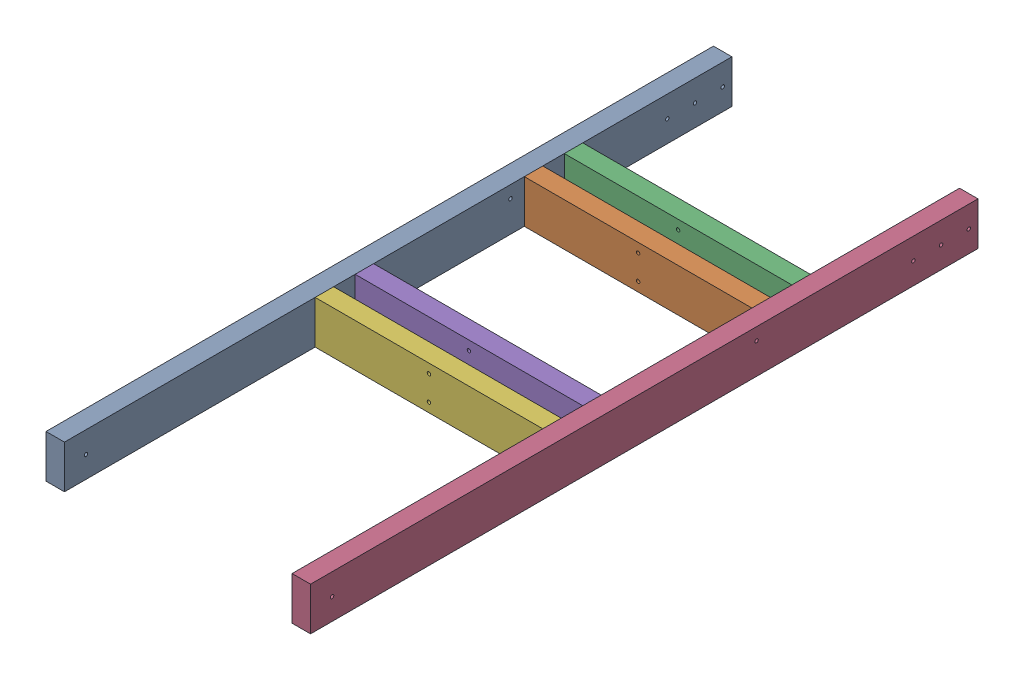
SolidWorks assembly TE-23031, configuration Default. Lengths in mm.
Overall size (546.1 88.9 1377.95).
6 component instances, 2 part files, 14 mates.
Components (placement in the parent):
- TE-23008-1: TE-23008 [Default] at (-254 44.45 0.7468) size (38.1 88.9 1377.95)
- TE-23010-2: TE-23010 [Default] at (-234.95 44.45 410.3218) x (0 0 -1) z (1 0 0) size (38.1 88.9 469.9)
- TE-23010-3: TE-23010 [Default] at (-234.95 44.45 327.7718) x (0 0 -1) z (1 0 0) size (38.1 88.9 469.9)
- TE-23008-2: TE-23008 [Default] at (254 44.45 0.7468) size (38.1 88.9 1377.95)
- TE-23010-4: TE-23010 [Default] at (-234.95 44.45 759.5718) x (0 0 -1) z (1 0 0) size (38.1 88.9 469.9)
- TE-23010-5: TE-23010 [Default] at (-234.95 44.45 842.1218) x (0 0 -1) z (1 0 0) size (38.1 88.9 469.9)
Mates (geometry in assembly coordinates):
- Coincident21: coincident aligned: plane of TE-23026-3 through (234.95 0 346.8218) normal (0 -1 0); plane of TE-23026-2 through (234.95 0 429.3718) normal (0 -1 0)
- Coincident25: coincident anti-aligned: plane of Cone Ramp Horizontal-1 through (-234.95 0 1378.6968) normal (1 0 0); plane of TE-23026-3 through (-234.95 44.45 327.7718) normal (-1 0 0)
- Coincident26: coincident anti-aligned: plane of Cone Ramp Horizontal-1 through (-234.95 0 1378.6968) normal (1 0 0); plane of TE-23026-2 through (-234.95 44.45 410.3218) normal (-1 0 0)
- Coincident34: coincident aligned: plane of Cone Ramp Horizontal-1 through (-273.05 0 1378.6968) normal (0 -1 0); plane of Cone Ramp Horizontal-2 through (234.95 0 1378.6968) normal (0 -1 0)
- Coincident36: coincident aligned: plane of Cone Ramp Horizontal-1 through (-254 44.45 0.7468) normal (0 0 -1); plane of Cone Ramp Horizontal-2 through (254 44.45 0.7468) normal (0 0 -1)
- Distance3: distance = 44.45 mm anti-aligned: plane of GE-23626-3 through (234.95 0 346.8218) normal (0 0 1); plane of GE-23626-2 through (234.95 0 391.2718) normal (0 0 -1)
- Distance5: distance = 307.975 mm aligned: plane of GE-23626-3 through (234.95 0 308.7218) normal (0 0 -1); plane of Cone Ramp Horizontal-1 through (-254 44.45 0.7468) normal (0 0 -1)
- Coincident41: coincident aligned: plane of TE-23011-1 through (-273.05 88.9 1378.6968) normal (0 1 0); plane of TE-23026-3 through (234.95 88.9 346.8218) normal (0 1 0)
- Coincident42: coincident aligned: plane of TE-23011-2 through (234.95 88.9 1378.6968) normal (0 1 0); plane of TE-23026-4 through (234.95 88.9 778.6218) normal (0 1 0)
- Distance6: distance = 311.15 mm anti-aligned: plane of TE-23026-4 through (234.95 0 740.5218) normal (0 0 -1); plane of TE-23026-2 through (234.95 0 429.3718) normal (0 0 1)
- Coincident44: coincident aligned: plane of TE-23011-1 through (-273.05 88.9 1378.6968) normal (0 1 0); plane of TE-23026-4 through (234.95 88.9 778.6218) normal (0 1 0)
- Distance7: distance = 44.45 mm anti-aligned: plane of TE-23026-4 through (234.95 0 778.6218) normal (0 0 1); plane of TE-23026-5 through (234.95 0 823.0718) normal (0 0 -1)
- Coincident46: coincident aligned: plane of TE-23026-4 through (234.95 88.9 778.6218) normal (0 1 0); plane of TE-23026-5 through (234.95 88.9 816.7218) normal (0 1 0)
- Coincident47: coincident anti-aligned: plane of TE-23011-1 through (-234.95 0 1378.6968) normal (1 0 0); plane of TE-23026-5 through (-234.95 44.45 797.6718) normal (-1 0 0)
